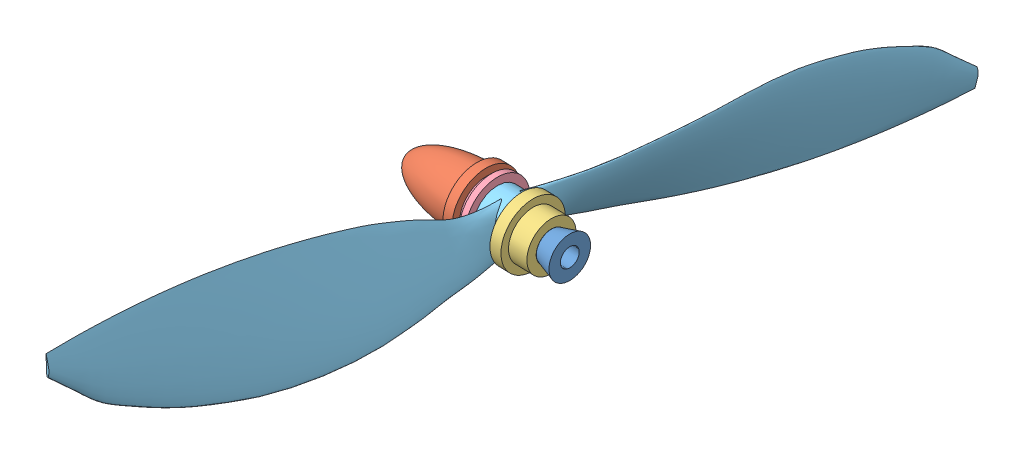
SolidWorks assembly Propeller_Yeet, configuration Default. Lengths in mm.
Overall size (454.99 60.19 286.89).
5 component instances, 5 part files, 9 mates.
Components (placement in the parent):
- Prop_Shaft_Clamp-4: Prop_Shaft_Clamp [Default] at (-410.44 0 163.83) x (-0.015148 0.000087 0.999885) z (-0.999797 0.013313 -0.015148) size (11.03 11.03 33.01)
- Prop_End_Cap-3: Prop_End_Cap [Default] at (-433.2354 0.3035 163.4846) x (-0.015148 0.000087 0.999885) z (-0.999797 0.013313 -0.015148) size (18 18 21.5)
- Prop_Bottom_Grip-3: Prop_Bottom_Grip [Default] at (-423.4374 0.1731 163.6331) x (0.015148 -0.000087 -0.999885) z (0.999797 -0.013313 0.015148) size (17 17 8)
- Prop_Top_Grip-3: Prop_Top_Grip [Default] at (-430.136 0.2623 163.5316) x (-0.015148 0.000087 0.999885) z (-0.999797 0.013313 -0.015148) size (17 17 3.1)
- 10x4.7-3: 10x4.7 [Default] at (-429.512 5.2548 159.7402) x (-0.013313 -0.999911 -0.000115) z (-0.015148 0.000087 0.999885) size (60.03 10.54 246.43)
Mates (geometry in assembly coordinates):
- Coincident9: coincident anti-aligned: circle of Prop_Shaft_Clamp-4; plane of Prop_Bottom_Grip-3 through (-415.44 163.819 0.0018) normal (0.999998 0.0022 -0.000365)
- Concentric9: concentric anti-aligned: cylinder of Prop_Shaft_Clamp-4 through (-443.4399 163.7574 0.012) axis (0.999998 0.0022 -0.000365) radius 4; cylinder of Prop_Bottom_Grip-3 through (-415.44 163.819 0.0018) axis (-0.999998 -0.0022 0.000365) radius 4.05
- Coincident10: coincident anti-aligned: plane of Prop_Bottom_Grip-3 through (-423.44 163.8014 0.0047) normal (-0.999998 -0.0022 0.000365); plane of 10x4.7-3 through (-423.44 163.8014 0.0047) normal (0.999998 0.0022 -0.000365)
- Concentric10: concentric anti-aligned: cylinder of Prop_Shaft_Clamp-4 through (-443.4399 163.7574 0.012) axis (0.999998 0.0022 -0.000365) radius 4; cylinder of 10x4.7-3 through (-425.64 163.7966 0.0055) axis (-0.999998 -0.0022 0.000365) radius 4
- Coincident11: coincident anti-aligned: plane of Prop_Top_Grip-3 through (-430.14 163.7867 0.0072) normal (0.999998 0.0022 -0.000365); plane of 10x4.7-3 through (-430.14 163.7867 0.0072) normal (-0.999998 -0.0022 0.000365)
- Concentric11: concentric aligned: cylinder of Prop_Shaft_Clamp-4 through (-443.4399 163.7574 0.012) axis (0.999998 0.0022 -0.000365) radius 4; cylinder of Prop_Top_Grip-3 through (-433.2399 163.7798 0.0083) axis (0.999998 0.0022 -0.000365) radius 4.05
- Coincident12: coincident anti-aligned: plane of Prop_End_Cap-3 through (-433.2399 163.7798 0.0083) normal (0.999998 0.0022 -0.000365); plane of Prop_Top_Grip-3 through (-433.2399 163.7798 0.0083) normal (-0.999998 -0.0022 0.000365)
- Concentric12: concentric aligned: cylinder of Prop_Shaft_Clamp-4 through (-443.4399 163.7574 0.012) axis (0.999998 0.0022 -0.000365) radius 4; cylinder of Prop_End_Cap-3 through (-452.2399 163.7381 0.0153) axis (0.999998 0.0022 -0.000365) radius 3.5
- Coincident15: coincident: unknown of Prop_Shaft_Clamp-4
